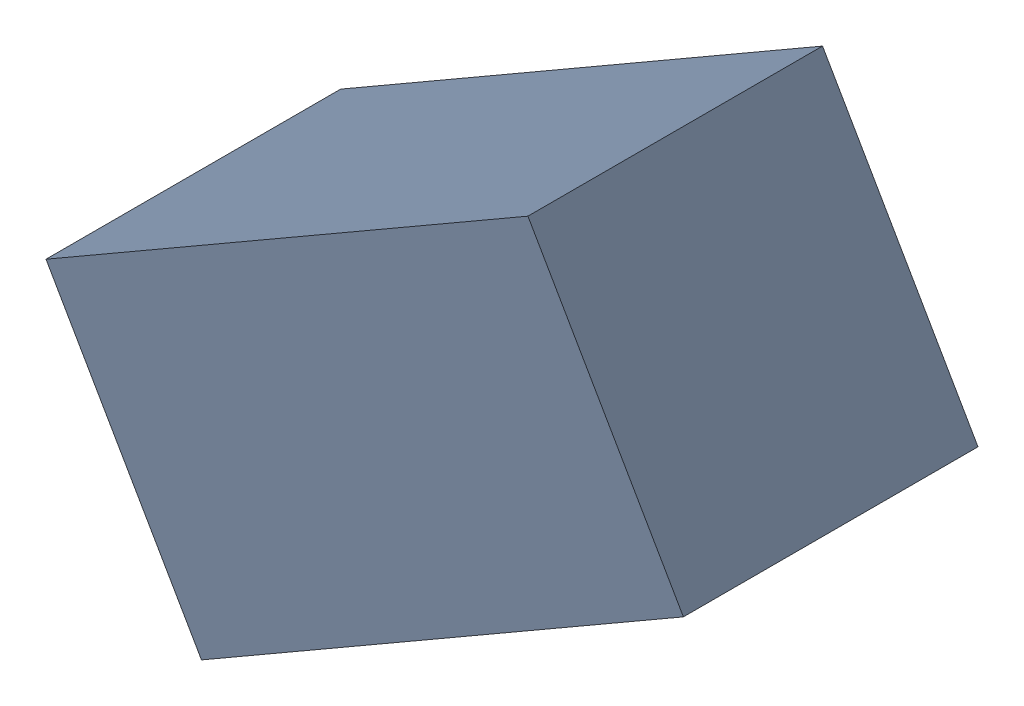
SolidWorks assembly R3_TDA2, configuration Standard. Lengths in mm.
Overall size (1.95 1.67 0.9).
2 component instances, 1 part files, 0 mates.
Components (placement in the parent):
- 885544008-1: 885544008 [Standard] at (47.2288 24.6924 0) size (1.95 1.67 0.9)
  - Extruded_15-1: Extruded_15 [Standard] at origin size (1.95 1.67 0.9)
